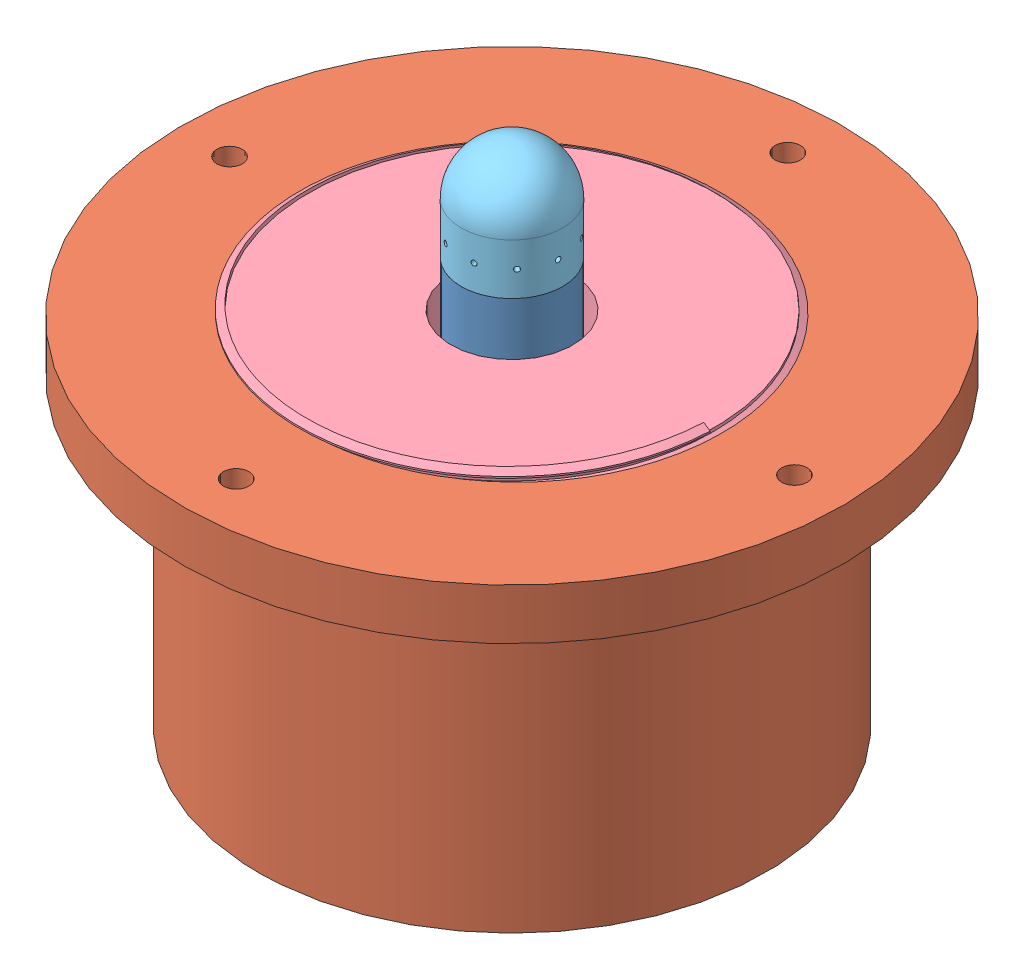
SolidWorks assembly Assem1, configuration Default. Lengths in mm.
Overall size (131.54 110 131.54).
5 component instances, 5 part files, 8 mates.
Components (placement in the parent):
- Part1-1: Part1 [Default] at (7.4356 16.6599 63.9037) size (50 90.29 50)
- Part2-1: Part2 [Default] at (7.4356 26.6599 63.9037) x (0.999929 0 -0.011885) z (0.011885 0 0.999929) size (130 70 130)
- orifice_plate-1: orifice_plate [Default] at (7.4356 66.6599 63.9037) x (0.988846 0 0.14894) z (-0.14894 0 0.988846) size (80 1 80)
- adjuster-1: adjuster [Default] at (7.4356 67.6599 63.9037) x (0.998531 0 0.054181) z (-0.054181 0 0.998531) size (82.71 31.87 86.96)
- pintle_tip-1: pintle_tip [Default] at (7.4356 106.6599 63.9037) x (0.655651 0 -0.755064) z (0.755064 0 0.655651) size (20 30 20)
Mates (geometry in assembly coordinates):
- Concentric1: concentric anti-aligned: cylinder of Part1-1 through (7.4356 106.6599 63.9037) axis (0 -1 0) radius 10; cylinder of Part2-1 through (7.4356 26.6599 63.9037) axis (0 1 0) radius 10
- Coincident1: coincident anti-aligned: plane of Part1-1 through (7.4356 26.6599 63.9037) normal (0 1 0); plane of Part2-1 through (7.4356 26.6599 63.9037) normal (0 -1 0)
- Concentric2: concentric aligned: cylinder of Part2-1 through (7.4356 66.6599 63.9037) axis (0 1 0) radius 40; circle of orifice_plate-1
- Coincident3: coincident anti-aligned: plane of Part2-1 through (7.4356 66.6599 63.9037) normal (0 1 0); plane of orifice_plate-1 through (7.4356 66.6599 63.9037) normal (0 -1 0)
- Concentric3: concentric anti-aligned: cylinder of Part1-1 through (7.4356 106.6599 63.9037) axis (0 -1 0) radius 10; cylinder of adjuster-1 through (7.4356 82.6599 63.9037) axis (0 1 0) radius 12
- Coincident4: coincident anti-aligned: plane of orifice_plate-1 through (7.4356 67.6599 63.9037) normal (0 1 0); plane of adjuster-1 through (7.4356 67.6599 63.9037) normal (0 -1 0)
- Concentric4: concentric aligned: cylinder of Part1-1 through (7.4356 16.6599 63.9037) axis (0 1 0) radius 5; cylinder of pintle_tip-1 through (7.4356 96.6599 63.9037) axis (0 1 0) radius 5
- Coincident5: coincident anti-aligned: plane of Part1-1 through (7.4356 106.6599 63.9037) normal (0 1 0); plane of pintle_tip-1 through (7.4356 106.6599 63.9037) normal (0 -1 0)
